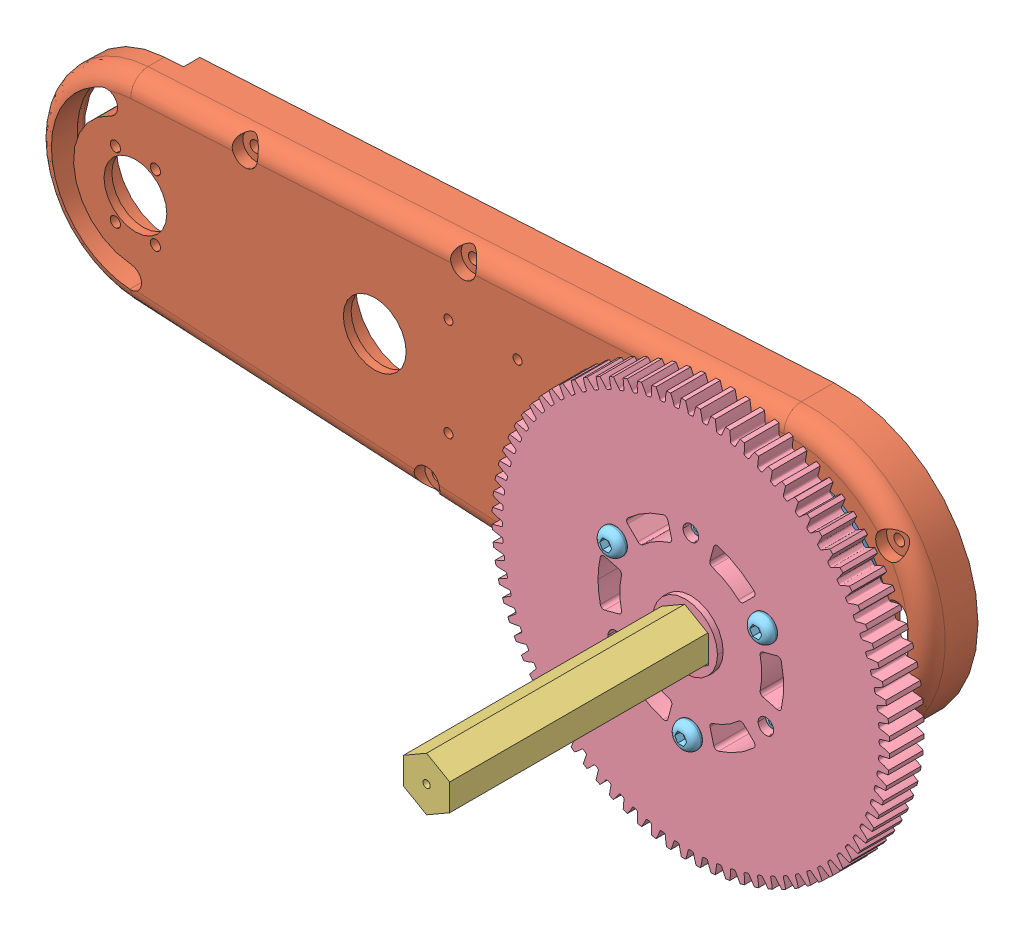
SolidWorks assembly Leg_Cover_Assembly, configuration Default. Lengths in mm.
Overall size (262.22 109.18 108).
14 component instances, 6 part files, 16 mates.
Components (placement in the parent):
- Leg_To_Hip_Adapter-1: Leg_To_Hip_Adapter [Default] at origin size (55 55 18)
- LegCover_EPOWER-1: LegCover_EPOWER [Default] at (0 0 -14) size (245 75 14.32)
- Hex_Shaft_Hip-2: Hex_Shaft_Hip [Default] x (0.866025 -0.5 0) z (0 0 1) size (14.66 12.7 94)
- 84T_SpurGear-1: 84T_SpurGear [Default] at (0.127 -0.22 22.7625) size (109.18 109.18 11.09)
- M4_30mm_Screw-1: M4_30mm_Screw [Default] at (0 23.8125 26) x (-0.923728 -0.383049 0) z (0 0 -1) size (7 7 32.81)
- M4_30mm_Screw-2: M4_30mm_Screw [Default] at (-20.6222 11.9062 26) x (-0.130134 -0.991496 0) z (0 0 -1) size (7 7 32.81) (hidden)
- M4_30mm_Screw-3: M4_30mm_Screw [Default] at (-20.6222 -11.9062 26) x (0.793594 -0.608447 0) z (0 0 -1) size (7 7 32.81)
- M4_30mm_Screw-4: M4_30mm_Screw [Default] at (0 -23.8125 26) x (0.923728 0.383049 0) z (0 0 -1) size (7 7 32.81) (hidden)
- M4_30mm_Screw-5: M4_30mm_Screw [Default] at (20.6222 -11.9062 26) x (0.130134 0.991496 0) z (0 0 -1) size (7 7 32.81)
- M4_30mm_Screw-6: M4_30mm_Screw [Default] at (20.6222 11.9062 26) x (-0.793594 0.608447 0) z (0 0 -1) size (7 7 32.81) (hidden)
- Shaft_Collar_Hex_Heavy_Duty-1: Shaft_Collar_Hex_Heavy_Duty [Default] at (0 0 9.525) x (-0.866025 0.5 0) z (-0.5 -0.866025 0) size (31.47 9.53 31.5)
- M4_30mm_Screw-8: M4_30mm_Screw [Default] at (20.7492 11.6863 -2.475) size (7 7 32.81)
- M4_30mm_Screw-9: M4_30mm_Screw [Default] at (-20.4952 11.6863 -2.475) x (-0.5 0.866025 0) z (0 0 1) size (7 7 32.81)
- M4_30mm_Screw-10: M4_30mm_Screw [Default] at (0.127 -24.0325 -2.475) x (-0.5 -0.866025 0) z (0 0 1) size (7 7 32.81)
Mates (geometry in assembly coordinates):
- Coincident1: coincident anti-aligned: plane of Leg_To_Hip_Adapter-1 through (0 0 0) normal (0 0 -1); plane of LegCover_EPOWER-1 through (0 0 0) normal (0 0 1)
- Concentric1: concentric aligned: circle of Leg_To_Hip_Adapter-1; circle of LegCover_EPOWER-1
- Concentric2: concentric aligned: circle of Leg_To_Hip_Adapter-1; circle of LegCover_EPOWER-1
- Coincident7: coincident anti-aligned: plane of LegCover_EPOWER-1 through (0 0 0) normal (0 0 1); plane of Hex_Shaft_Hip-2 through (0 0 0) normal (0 0 -1)
- Concentric3: concentric aligned: circle of Leg_To_Hip_Adapter-1; circle of Hex_Shaft_Hip-2
- Parallel1: parallel anti-aligned: plane of Leg_To_Hip_Adapter-1 through (0 7.4497 18) normal (-0.5 -0.866025 0); plane of Hex_Shaft_Hip-2 through (6.35 3.6662 94) normal (0.5 0.866025 0)
- Coincident9: coincident anti-aligned: plane of Hex_Shaft_Hip-2 through (-6.35 3.6662 94) normal (-1 0 0); plane of 84T_SpurGear-1 through (-6.35 3.5195 18) normal (1 0 0)
- Coincident10: coincident anti-aligned: plane of Hex_Shaft_Hip-2 through (6.35 3.6662 94) normal (0.5 0.866025 0); plane of 84T_SpurGear-1 through (6.604 3.5195 18) normal (-0.5 -0.866025 0)
- Coincident11: coincident anti-aligned: plane of Leg_To_Hip_Adapter-1 through (0 0 18) normal (0 0 1); plane of 84T_SpurGear-1 through (0.127 54.39 18) normal (0 0 -1)
- Coincident12: coincident anti-aligned: plane of LegCover_EPOWER-1 through (0 0 -4) normal (0 0 -1); plane of M4_30mm_Screw-1 through (0 23.8125 -4) normal (0 0 1)
- Concentric4: concentric aligned: circle of LegCover_EPOWER-1; circle of M4_30mm_Screw-1
- Concentric5: concentric aligned: circle of Leg_To_Hip_Adapter-1; circle of Shaft_Collar_Hex_Heavy_Duty-1
- Coincident17: coincident anti-aligned: plane of Hex_Shaft_Hip-2 through (6.35 3.6662 94) normal (0.5 0.866025 0); plane of Shaft_Collar_Hex_Heavy_Duty-1 through (0 7.3323 0) normal (-0.5 -0.866025 0)
- Coincident18: coincident anti-aligned: plane of LegCover_EPOWER-1 through (0 0 0) normal (0 0 1); plane of Shaft_Collar_Hex_Heavy_Duty-1 through (0 0 0) normal (0 0 -1)
- Concentric8: concentric aligned: circle of 84T_SpurGear-1; circle of M4_30mm_Screw-8
- Coincident19: coincident anti-aligned: plane of 84T_SpurGear-1 through (0.127 -0.22 27.525) normal (0 0 1); plane of M4_30mm_Screw-8 through (20.7492 11.6863 27.525) normal (0 0 -1)
